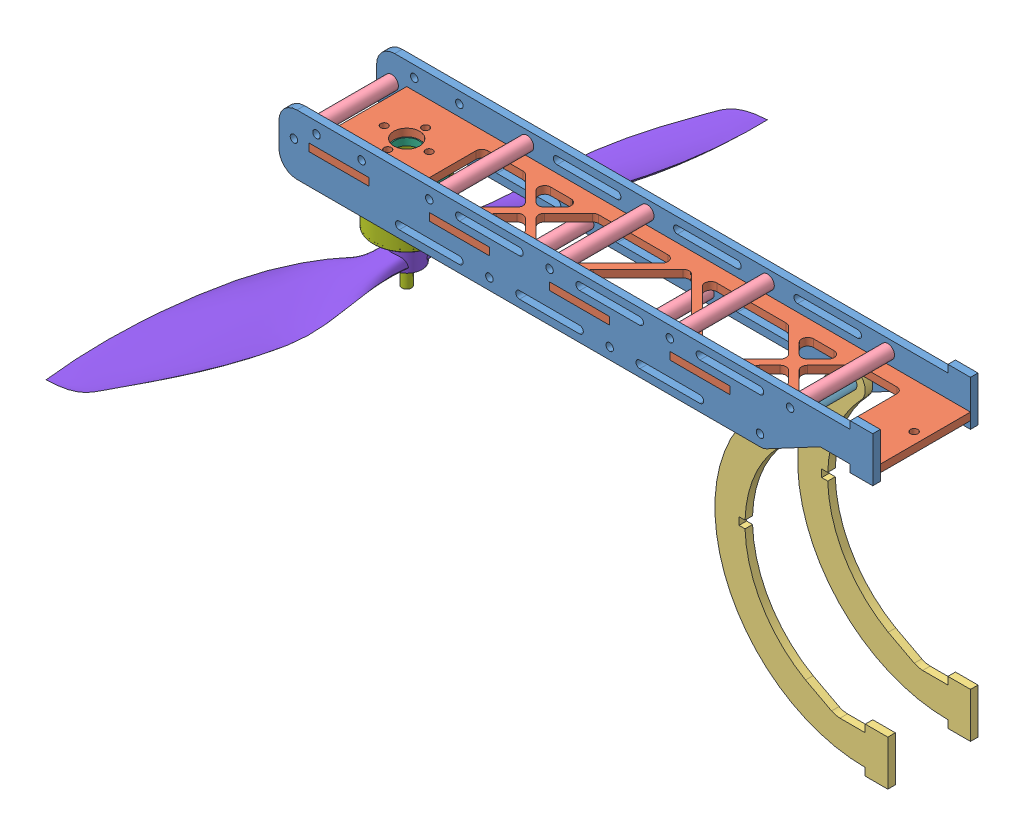
SolidWorks assembly arm - assy - F, configuration Default. Lengths in mm.
Overall size (268.19 130.02 255.49).
17 component instances, 8 part files, 19 mates.
Components (placement in the parent):
- arm - F-1: arm - F [Default] at (7.8754 -24.9369 12.786) size (250.83 28.57 3.17)
- arm-center - F-1: arm-center - F [Default] at (-76.2706 -4.6579 -11.069) x (1 0 0) z (0 1 0) size (238.12 44.45 3.17)
- arm - F-2: arm - F [Default] at (7.8754 -24.9369 -28.489) size (250.83 28.57 3.17)
- arm-piece - F-1: arm-piece - F [Default] at (-66.1286 -74.8964 9.611) size (73.03 112.55 3.17)
- arm-piece - F-2: arm-piece - F [Default] at (-66.1286 -74.8964 -25.314) size (73.03 112.55 3.17)
- spacer - F-1: spacer - F [Default] at (-75.7599 -12.5954 -25.314) size (5.71 5.71 38.1)
- spacer - F-2: spacer - F [Default] at (51.2401 3.2796 -25.314) size (5.71 5.71 38.1)
- spacer - F-3: spacer - F [Default] at (-101.1599 3.2796 -25.314) size (5.71 5.71 38.1)
- spacer - F-4: spacer - F [Default] at (-24.9599 -12.5954 -25.314) size (5.71 5.71 38.1)
- spacer - F-5: spacer - F [Default] at (-50.3599 3.2796 -25.314) size (5.71 5.71 38.1)
- spacer - F-6: spacer - F [Default] at (0.4401 3.2796 -25.314) size (5.71 5.71 38.1)
- spacer - F-7: spacer - F [Default] at (-158.3099 -3.0704 -25.314) size (5.71 5.71 38.1)
- spacer - Short - F-1: spacer - Short - F [Default] at (38.5401 -12.5954 -22.139) size (5.71 5.71 31.75)
- motor-assy-1: motor-assy [Default] at (-134.2321 -7.4751 -6.6678) x (-1 0 0) z (0 0 1) size (91.88 50.5 255.49)
  - motor-bot2-1: motor-bot2 [Default] at (-1.3226 -2.8172 0.4038) size (27.94 6.5 27.94)
  - motor2-1: motor2 [Default] at (-1.3226 3.6828 0.4038) size (28 44 28)
  - prop-1: prop [Default] at (-1.3226 34.6828 0.4038) x (0.974272 0 -0.225375) z (0.225375 0 0.974272) size (35.55 10.91 254.01)
Mates (geometry in assembly coordinates):
- Coincident1: coincident aligned: line of arm - F-1 through (-126.5599 -1.4829 15.961) axis (0 -1 0); line of arm-center - F-1 through (-126.5599 -1.4829 15.961) axis (0 -1 0)
- Coincident3: coincident aligned: line of arm-center - F-1 through (-126.5599 -1.4829 -28.489) axis (0 -1 0); line of arm - F-2 through (-126.5599 -1.4829 -28.489) axis (0 -1 0)
- Coincident5: coincident aligned: circle of arm - F-1; circle of arm-piece - F-1
- Coincident6: coincident aligned: circle of arm - F-2; circle of arm-piece - F-2
- Coincident8: coincident aligned: plane of arm - F-1 through (38.8576 -12.2779 15.961) normal (0 0 1); plane of arm-center - F-1 through (-151.9599 -1.4829 15.961) normal (0 0 1)
- Coincident9: coincident anti-aligned: plane of arm - F-1 through (-151.9599 -4.6579 15.961) normal (0 1 0); plane of arm-center - F-1 through (-76.2706 -4.6579 -11.069) normal (0 -1 0)
- Coincident11: coincident anti-aligned: plane of arm-center - F-1 through (-76.2706 -4.6579 -11.069) normal (0 -1 0); plane of arm - F-2 through (0.4401 -4.6579 -25.314) normal (0 1 0)
- Coincident12: coincident aligned: plane of arm-center - F-1 through (0.4401 -1.4829 -28.489) normal (0 0 -1); plane of arm - F-2 through (38.8576 -12.2779 -28.489) normal (0 0 -1)
- Coincident13: coincident aligned: circle of arm - F-2; circle of spacer - F-1
- Coincident14: coincident aligned: circle of arm - F-2; circle of spacer - F-4
- Coincident15: coincident aligned: circle of arm - F-2; circle of spacer - F-3
- Coincident16: coincident aligned: circle of arm - F-2; circle of spacer - F-5
- Coincident17: coincident aligned: circle of arm - F-2; circle of spacer - F-2
- Coincident18: coincident aligned: circle of arm - F-2; circle of spacer - F-7
- Coincident19: coincident aligned: circle of arm - F-2; circle of spacer - F-6
- Coincident20: coincident aligned: circle of arm-piece - F-2; circle of spacer - Short - F-1
- Coincident21: coincident: plane of arm-center - F-1 through (-76.2706 -4.6579 -11.069) normal (0 -1 0); plane of motor-assy-1/motor-bot2-1 through (-120.7655 -4.6579 -18.408) normal (0 1 0)
- Concentric1: concentric: cylinder of arm-center - F-1 through (-142.4095 -1.4829 -6.264) axis (0 -1 0) radius 1.524; cylinder of motor-assy-1/motor-bot2-1 through (-142.4095 -4.6579 -6.264) axis (0 1 0) radius 1.45
- Concentric2: concentric anti-aligned: cylinder of arm-center - F-1 through (-123.4103 -1.4829 -6.264) axis (0 -1 0) radius 1.524; cylinder of motor-assy-1/motor-bot2-1 through (-123.4095 -4.6579 -6.264) axis (0 1 0) radius 1.45
